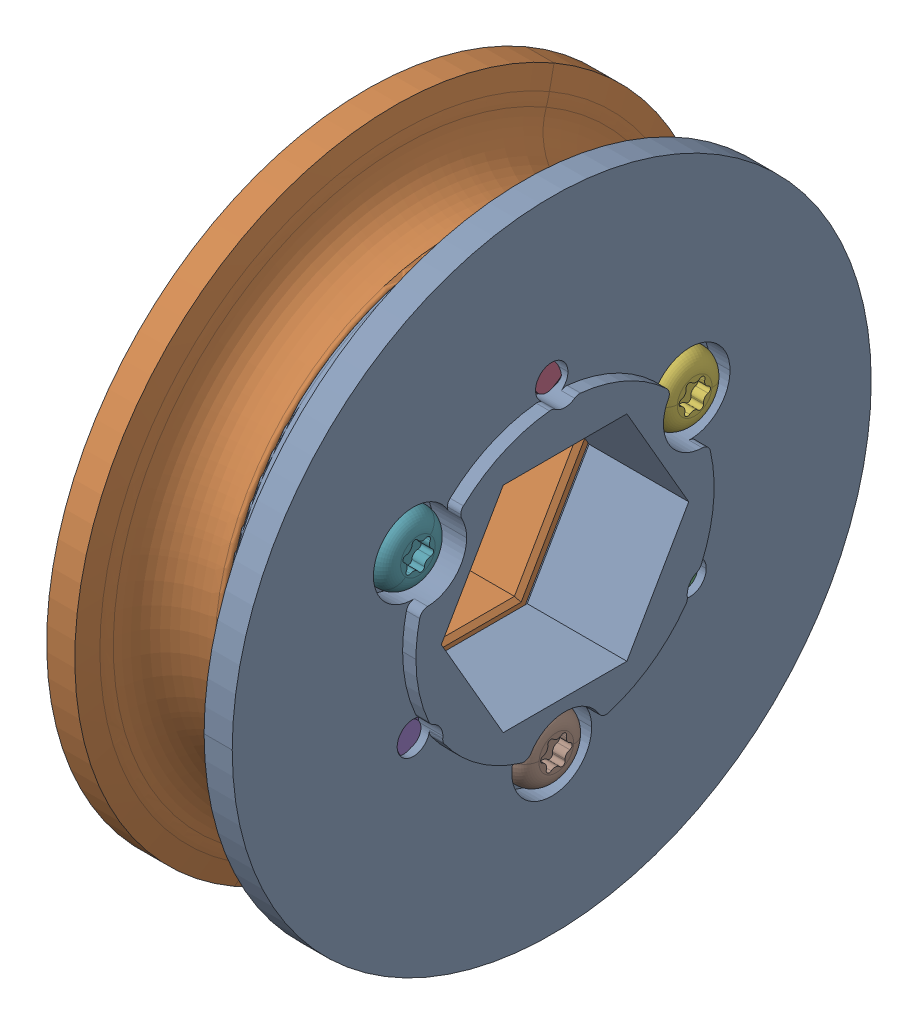
SolidWorks assembly WCP-0096 Rev6-5.step, configuration Default. Lengths in mm.
Overall size (12.65 52.05 52.05).
8 component instances, 2 part files, 0 mates.
Components (placement in the parent):
- WCP-0096-001 Rev6.step-1: WCP-0096-001 Rev6.step [Default] at origin size (7.57 38.1 38.1)
- WCP-0096-001 Rev6.step-2: WCP-0096-001 Rev6.step [Default] x (-1 0 0) z (0 0.866025 -0.5) size (7.57 38.1 38.1)
- WCP-0356 Rev1.step-1: WCP-0356 Rev1.step [Default] at (0.4817 -4.7625 -8.2489) x (0 -0.126969 0.991907) z (0 -0.991907 -0.126969) size (4.06 11.05 4.06)
- WCP-0356 Rev1.step-2: WCP-0356 Rev1.step [Default] at (0.4817 9.525 0) x (0 0.866766 0.498715) z (0 -0.498715 0.866766) size (4.06 11.05 4.06)
- WCP-0356 Rev1.step-3: WCP-0356 Rev1.step [Default] at (0.4817 -4.7625 8.2489) x (0 -0.994015 -0.109248) z (0 0.109248 -0.994015) size (4.06 11.05 4.06)
- WCP-0356 Rev1.step-4: WCP-0356 Rev1.step [Default] at (-0.4817 4.7625 -8.2489) x (0 -0.997555 0.069879) z (0 0.069879 0.997555) size (4.06 11.05 4.06)
- WCP-0356 Rev1.step-5: WCP-0356 Rev1.step [Default] at (-0.4817 4.7625 8.2489) x (0 -0.7202 -0.693767) z (0 -0.693767 0.7202) size (4.06 11.05 4.06)
- WCP-0356 Rev1.step-6: WCP-0356 Rev1.step [Default] at (-0.4817 -9.525 0) x (0 -0.997555 0.069879) z (0 0.069879 0.997555) size (4.06 11.05 4.06)
